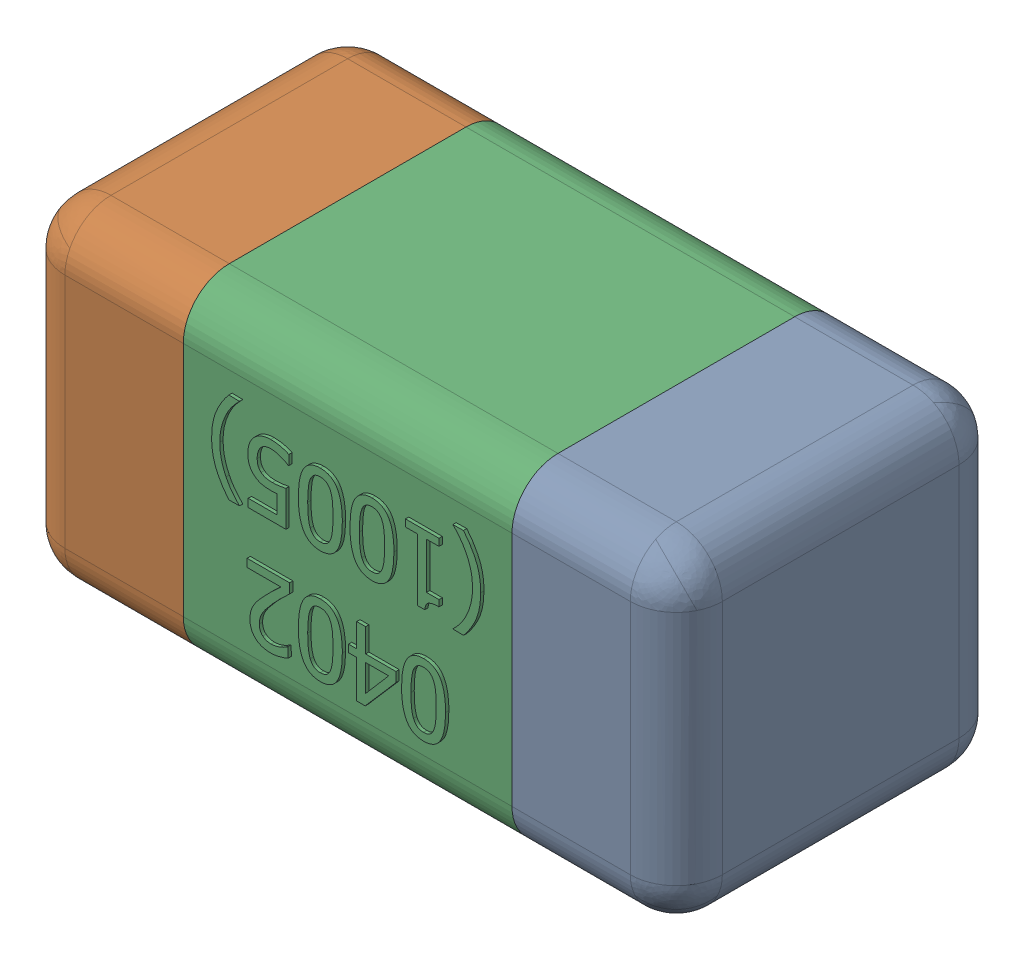
SolidWorks assembly C6, configuration Standard. Lengths in mm.
Overall size (1.01 0.51 0.51).
4 component instances, 3 part files, 0 mates.
Components (placement in the parent):
- C6-subassembly-1-1: C6-subassembly-1 [Standard] at (-3.0001 6.1 0) x (-1 0 0) z (0 0 1) size (1.01 0.51 0.51)
  - User Library-0402_Cap-1: User Library-0402_Cap [Standard] at origin size (0.26 0.51 0.51)
  - User Library-0402_Cap-1-1: User Library-0402_Cap-1 [Standard] at origin size (0.26 0.5 0.51)
  - User Library-0402_Cap-2-1: User Library-0402_Cap-2 [Standard] at origin size (0.5 0.5 0.51)
